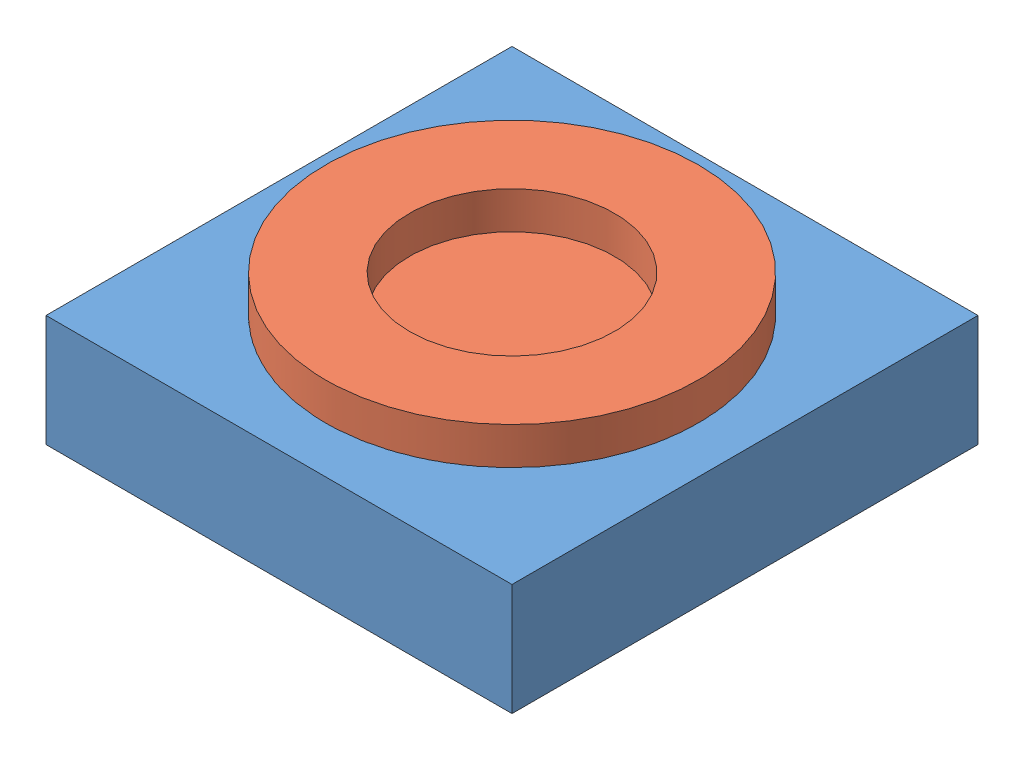
SolidWorks assembly C_10m_5t_mold, configuration Default. Lengths in mm.
Overall size (25 8 25).
2 component instances, 2 part files, 2 mates.
Components (placement in the parent):
- C_10m_5t_mold-1: C_10m_5t_mold [Default] at (8.6575 12.9126 19.6363) size (25 6 25)
- C_10m_5t-1: C_10m_5t [Default] at (8.6575 15.9126 19.6363) size (20 5 20)
Mates (geometry in assembly coordinates):
- Coincident5: coincident aligned: plane of C_10m_5t_mold-1 through (8.6575 18.9126 19.6363) normal (0 1 0); plane of C_10m_5t-1 through (8.6575 18.9126 19.6363) normal (0 1 0)
- Coincident9: coincident: line of C_10m_5t-1 through (8.6575 20.9126 19.6363) axis (0 -1 0)
